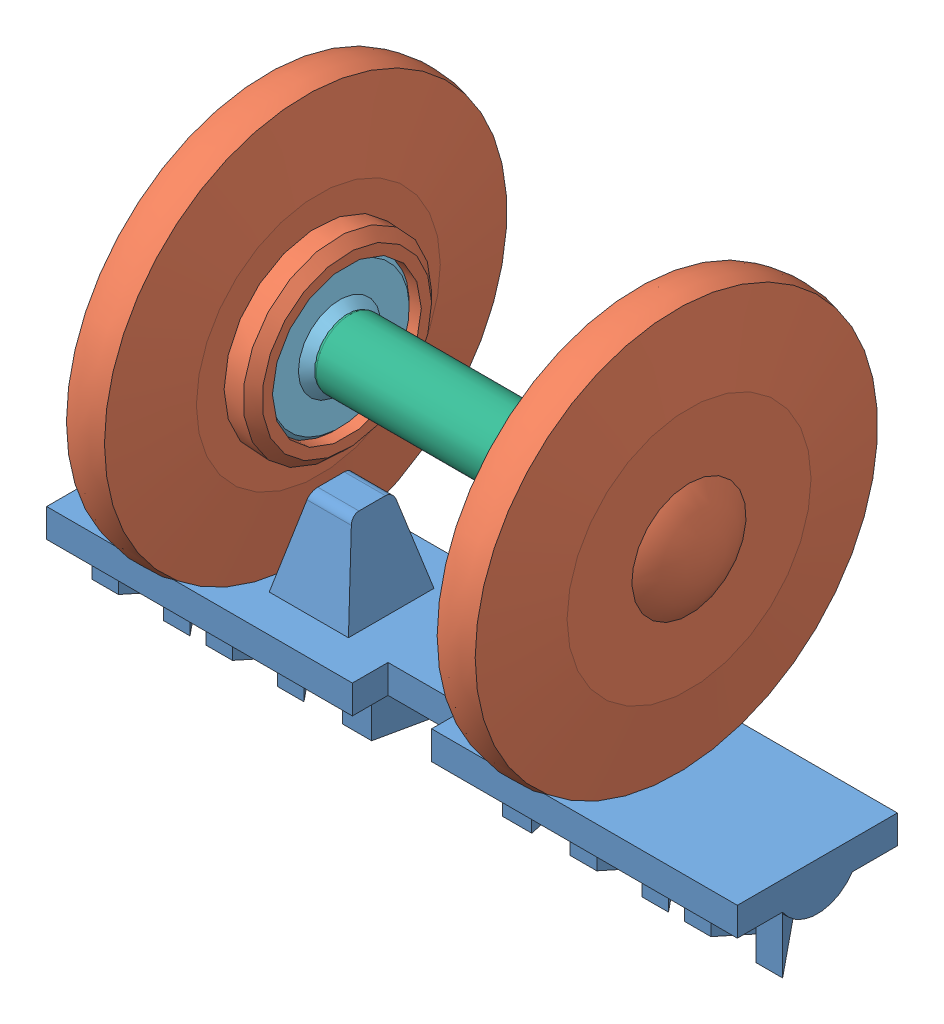
SolidWorks assembly Проект оси катков, configuration 00. Lengths in mm.
Overall size (218.02 156 129).
12 component instances, 6 part files, 10 mates.
Components (placement in the parent):
- Трак гусеницы-1: Трак гусеницы [По умолчанию] at (0 -9 0) x (-1 0 0) z (0 0 1) size (218.02 54 50.5)
- Каток 129(47) в сборе-1: Каток 129(47) в сборе [00] at (58.5 64.5 0) size (35.7 129 129)
  - Каток 129(47)-1: Каток 129(47) [--] at origin size (35 129 129)
  - Подшипник ГОСТ 8338-75 -1: Подшипник ГОСТ 8338-75  [Подшипник 204 ГОСТ 8338-75] at (-1 0 0) x (1 0 0) z (0 -0.327433 -0.944874) size (14 47 47)
  - Стопор внутренний до 165мм (ГОСТ 13943-86)-1: Стопор внутренний до 165мм (ГОСТ 13943-86) [Кольцо 47] at (-8 0 0) x (0 0.910839 0.412761) z (-1 0 0) size (49.5 51.2 1.7)
  - Сальник 47х20-1: Сальник 47х20 [--] at (-9.7 0 0) x (-1 0 0) z (0 0.937697 -0.347453) size (10 47 47)
- Каток 129(47) в сборе-2: Каток 129(47) в сборе [00] at (-58.5 64.5 0) x (-1 0 0) z (0 0 1) size (35.7 129 129)
  - Каток 129(47)-1: Каток 129(47) [--] at origin size (35 129 129)
  - Подшипник ГОСТ 8338-75 -1: Подшипник ГОСТ 8338-75  [Подшипник 204 ГОСТ 8338-75] at (-1 0 0) x (1 0 0) z (0 -0.327433 -0.944874) size (14 47 47)
  - Стопор внутренний до 165мм (ГОСТ 13943-86)-1: Стопор внутренний до 165мм (ГОСТ 13943-86) [Кольцо 47] at (-8 0 0) x (0 0.910839 0.412761) z (-1 0 0) size (49.5 51.2 1.7)
  - Сальник 47х20-1: Сальник 47х20 [--] at (-9.7 0 0) x (-1 0 0) z (0 0.937697 -0.347453) size (10 47 47)
- ТП.016.02.01.01.02 - Ось-1: ТП.016.02.01.01.02 - Ось [--] at (0 64.5 0) size (129 21.3 21.3)
Mates (geometry in assembly coordinates):
- Совпадение1: coincident: plane of Трак гусеницы-1 through (-109 0 25.25) normal (0 1 0); plane of assembly through (0 0 0) normal (0 1 0)
- Совпадение2: coincident: plane of Трак гусеницы-1 through (0 -9 0) normal (0 0 -1); plane of assembly through (0 0 0) normal (0 0 1)
- Совпадение3: coincident: plane of Трак гусеницы-1 through (0 -9 0) normal (1 0 0); plane of assembly through (0 0 0) normal (1 0 0)
- Касательность1: tangent: plane of Трак гусеницы-1 through (-109 0 25.25) normal (0 1 0); torus of Каток 129(47) в сборе-1/Каток 129(47)-1
- Совпадение4: coincident: plane of Каток 129(47) в сборе-1/Каток 129(47)-1 through (58.5 64.5 0) normal (0 0 1); plane of assembly through (0 0 0) normal (0 0 1)
- Параллельность1: parallel: plane of Каток 129(47) в сборе-1/Каток 129(47)-1 through (58.5 64.5 0) normal (1 0 0); plane of assembly through (0 0 0) normal (1 0 0)
- Расстояние1: distance = 2 mm: line of Трак гусеницы-1 through (50.5 0 13.5) axis (0 0 -1); plane of Каток 129(47) в сборе-1/Каток 129(47)-1 through (48.5 94.25 0) normal (-1 0 0)
- Совпадение5: coincident: plane of ТП.016.02.01.01.02 - Ось-1 through (0 64.5 0) normal (1 0 0); plane of assembly through (0 0 0) normal (1 0 0)
- Совпадение6: coincident: plane of Каток 129(47) в сборе-1/Каток 129(47)-1 through (58.5 64.5 0) normal (0 1 0); plane of ТП.016.02.01.01.02 - Ось-1 through (0 64.5 0) normal (0 1 0)
- Совпадение7: coincident: plane of Каток 129(47) в сборе-1/Каток 129(47)-1 through (58.5 64.5 0) normal (0 0 1); plane of ТП.016.02.01.01.02 - Ось-1 through (0 64.5 0) normal (0 0 1)
